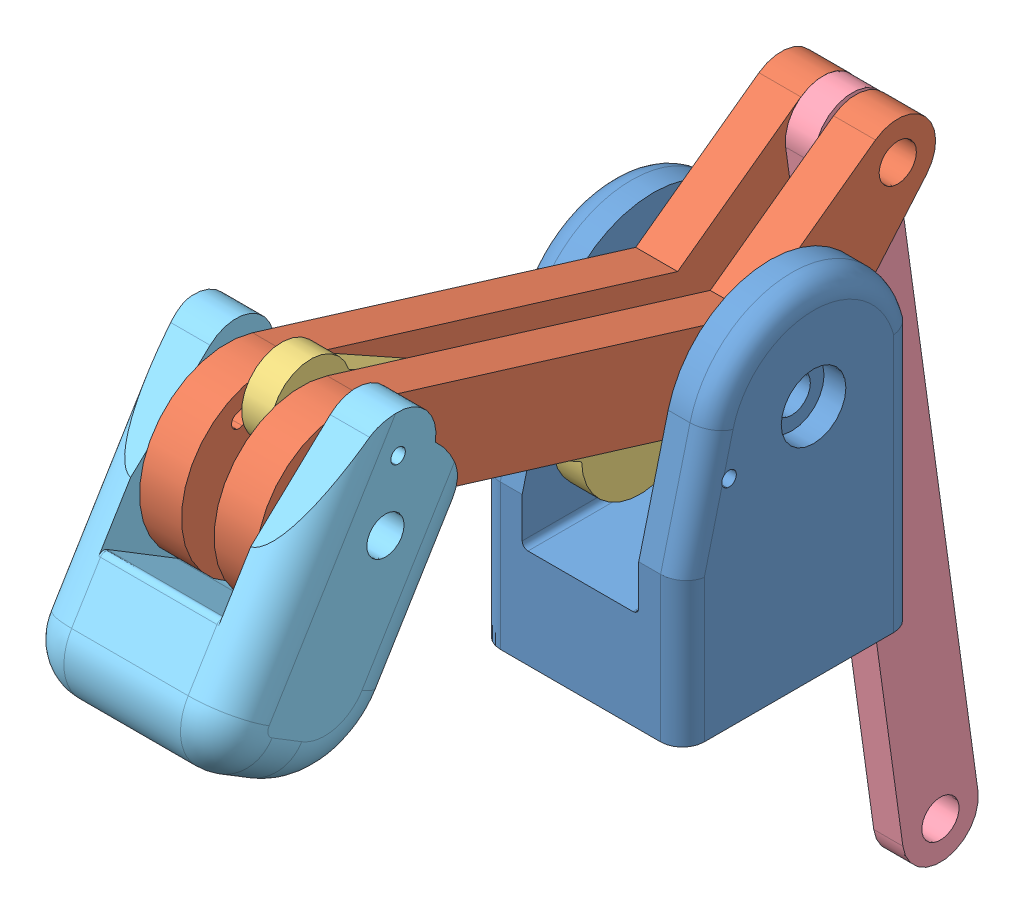
SolidWorks assembly Thumb, configuration Default. Lengths in mm.
Overall size (17.69 76.61 74.32).
6 component instances, 5 part files, 12 mates.
Components (placement in the parent):
- base-1: base [Default] at (-2.6093 9.3209 33.628) size (17.57 29.25 20)
- Joint1A-1: Joint1A [Default] at (4.7407 29.5709 42.378) x (0 -0.955992 0.293394) z (-1 0 0) size (26.75 55.59 3.6)
- Joint1A-2: Joint1A [Default] at (11.1407 29.5709 42.378) x (0 -0.955992 0.293394) z (-1 0 0) size (26.75 55.59 3.6)
- Link1A-1: Link1A [shorter] at (4.7407 27.8209 49.628) x (0 0.873351 -0.487092) z (0 -0.487092 -0.873351) size (10 2.5 40.77)
- Link3A-1: Link3A [Default] at (4.7407 40.3245 31.4044) x (0 0.99051 0.137442) z (1 0 0) size (61.5 6.5 2.5)
- ThumbTip-1: ThumbTip [Default] at (5.9907 38.1832 78.9612) x (0 0.520929 0.8536) z (1 0 0) size (15.03 25.92 17.5)
Mates (geometry in assembly coordinates):
- Concentric1: concentric aligned: cylinder of Joint1A-1 through (1.1407 29.5709 42.378) axis (1 0 0) radius 1.6; cylinder of Joint1A-2 through (7.5407 29.5709 42.378) axis (1 0 0) radius 1.6
- Coincident1: coincident anti-aligned: plane of base-1 through (11.1407 17.8209 53.628) normal (-1 0 0); plane of Joint1A-2 through (11.1407 38.1832 78.9612) normal (1 0 0)
- Coincident2: coincident anti-aligned: plane of base-1 through (1.1407 39.3209 53.628) normal (1 0 0); plane of Joint1A-1 through (1.1407 38.1832 78.9612) normal (-1 0 0)
- Concentric3: concentric anti-aligned: cylinder of base-1 through (-2.6093 27.8209 49.628) axis (1 0 0) radius 0.625; cylinder of Link1A-1 through (7.2407 27.8209 49.628) axis (-1 0 0) radius 0.625
- Coincident3: coincident anti-aligned: plane of Joint1A-1 through (4.7407 38.1832 78.9612) normal (1 0 0); plane of Link1A-1 through (4.7407 43.5748 77.8746) normal (-1 0 0)
- Concentric4: concentric anti-aligned: cylinder of Joint1A-1 through (1.1407 40.3245 31.4044) axis (1 0 0) radius 1.6; cylinder of Link3A-1 through (7.2407 40.3245 31.4044) axis (-1 0 0) radius 1.6
- Coincident4: coincident anti-aligned: plane of Joint1A-1 through (4.7407 38.1832 78.9612) normal (1 0 0); plane of Link3A-1 through (4.7407 -14.1535 23.8451) normal (-1 0 0)
- Concentric7: concentric aligned: cylinder of base-1 through (-2.6093 29.5709 42.378) axis (1 0 0) radius 1.6; cylinder of Joint1A-1 through (1.1407 29.5709 42.378) axis (1 0 0) radius 1.6
- Concentric10: concentric aligned: cylinder of Joint1A-1 through (1.1407 38.1832 78.9612) axis (1 0 0) radius 1.6; cylinder of ThumbTip-1 through (-2.7593 38.1832 78.9612) axis (1 0 0) radius 1.6
- Coincident7: coincident anti-aligned: plane of Joint1A-2 through (11.1407 38.1832 78.9612) normal (1 0 0); plane of ThumbTip-1 through (11.1407 38.1832 78.9612) normal (-1 0 0)
- Coincident8: coincident anti-aligned: circle of Link1A-1; cylinder of ThumbTip-1 through (14.7407 43.5748 77.8746) axis (-1 0 0) radius 0.625
- Coincident9: coincident aligned: cylinder of Joint1A-2 through (7.5407 38.1832 78.9612) axis (1 0 0) radius 1.6; circle of ThumbTip-1
